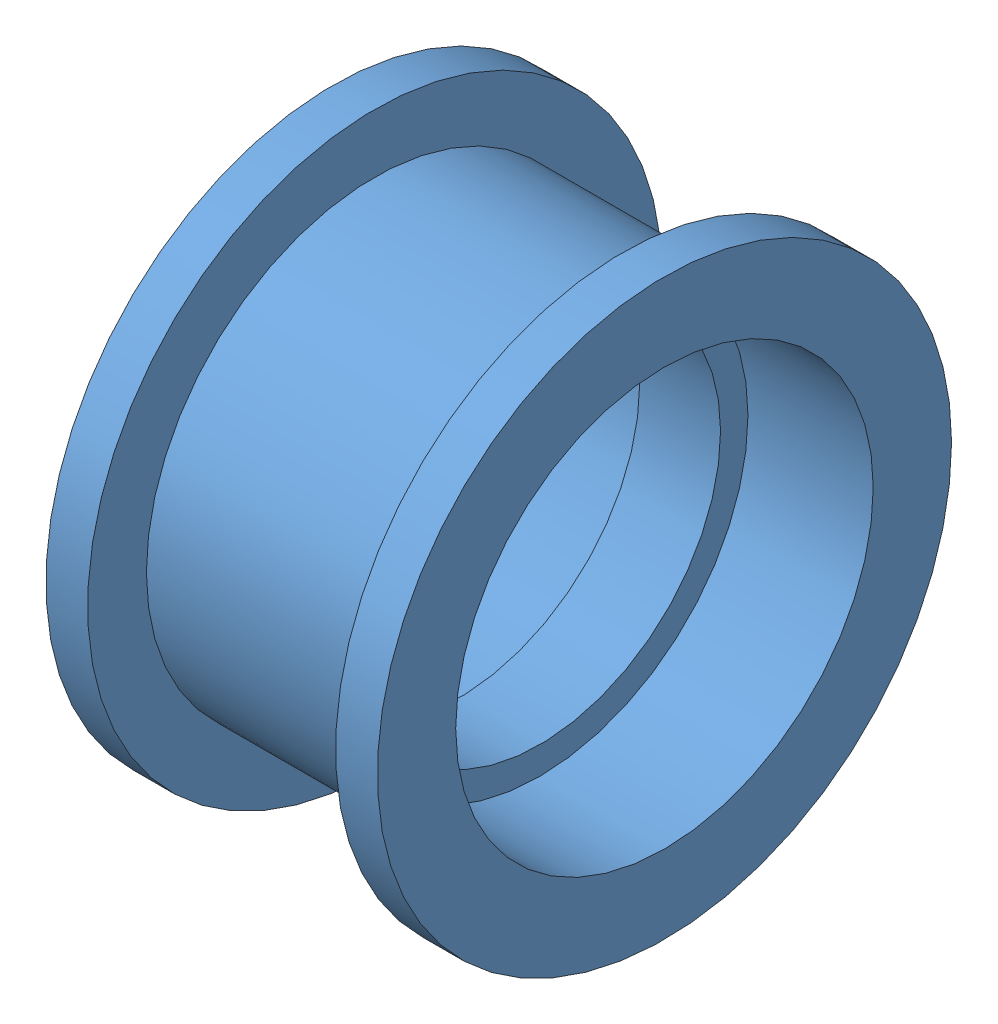
SolidWorks assembly Smooth Idler Pulley Wheel, configuration 預設. Lengths in mm.
Overall size (12.7 22 22).
3 component instances, 2 part files, 2 mates.
Components (placement in the parent):
- Smooth Idler Pulley Wheel-1: Smooth Idler Pulley Wheel [Default] at (-6.4593 1.4834 22) size (12.7 22 22)
- 625zz_5x16x5mm-1: 625zz_5x16x5mm [預設] at (-2.6093 1.4834 22) x (0 0 -1) z (1 0 0) (suppressed, hidden)
- 625zz_5x16x5mm-2: 625zz_5x16x5mm [預設] at (-10.3093 1.4834 22) x (0 0 -1) z (1 0 0) (suppressed, hidden)
Mates (geometry in assembly coordinates):
- 重合/共線/共點1: coincident: circle of Smooth Idler Pulley Wheel-1; circle of 625zz_5x16x5mm-1
- 重合/共線/共點2: coincident: circle of Smooth Idler Pulley Wheel-1; circle of 625zz_5x16x5mm-2
